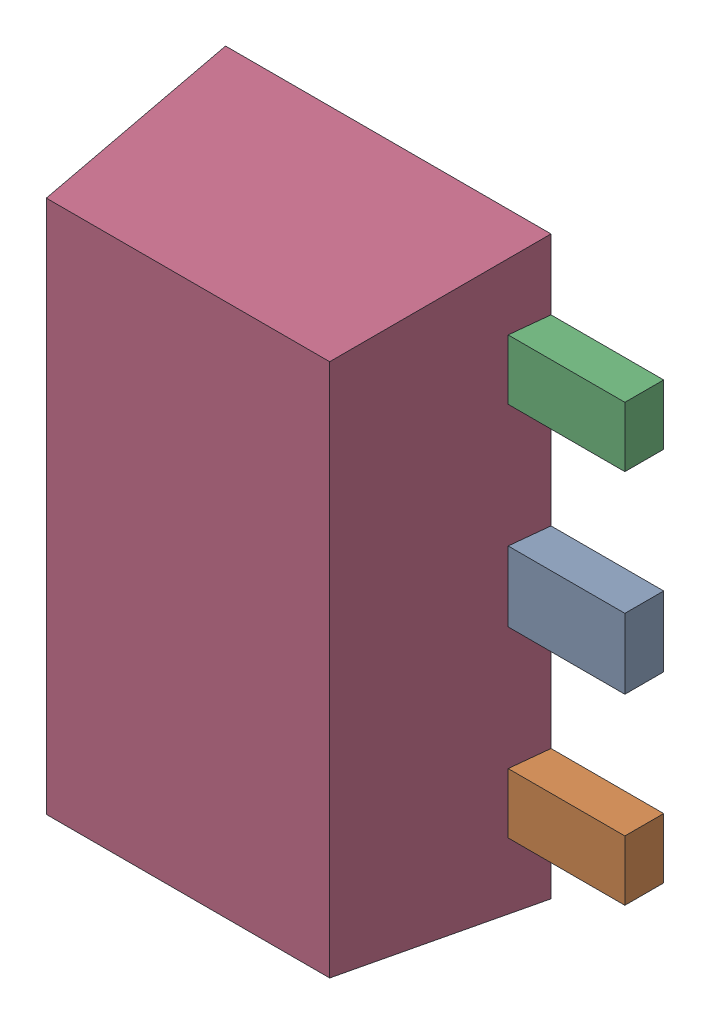
SolidWorks assembly IC1, configuration 默认. Lengths in mm.
Overall size (4.05 4.6 1.6).
7 component instances, 4 part files, 0 mates.
Components (placement in the parent):
- 6517555664-1: 6517555664 [默认] at (112.3188 90.2716 0) x (-1 0 0) z (0 0 1) size (4.05 4.6 1.6)
  - CenterLeader-1: CenterLeader [默认] at (-1.3 -2.3 0) size (4.05 1.83 0.31)
    - Open_CASCADE_STEP_translator_6.8_1.1.1-1: Open_CASCADE_STEP_translator_6.8_1.1.1 [默认] at origin size (4.05 1.83 0.31)
  - top-1: top [默认] at (-1.3 -2.3 0) size (1.2 0.48 0.31)
  - bottom-1: bottom [默认] at (-1.3 -2.3 0) size (1.2 0.48 0.31)
  - Body-1: Body [默认] at (-1.3 -2.3 0) size (2.6 4.6 1.6)
    - Open_CASCADE_STEP_translator_6.8_1.4.1-1: Open_CASCADE_STEP_translator_6.8_1.4.1 [默认] at origin size (2.6 4.6 1.6)
